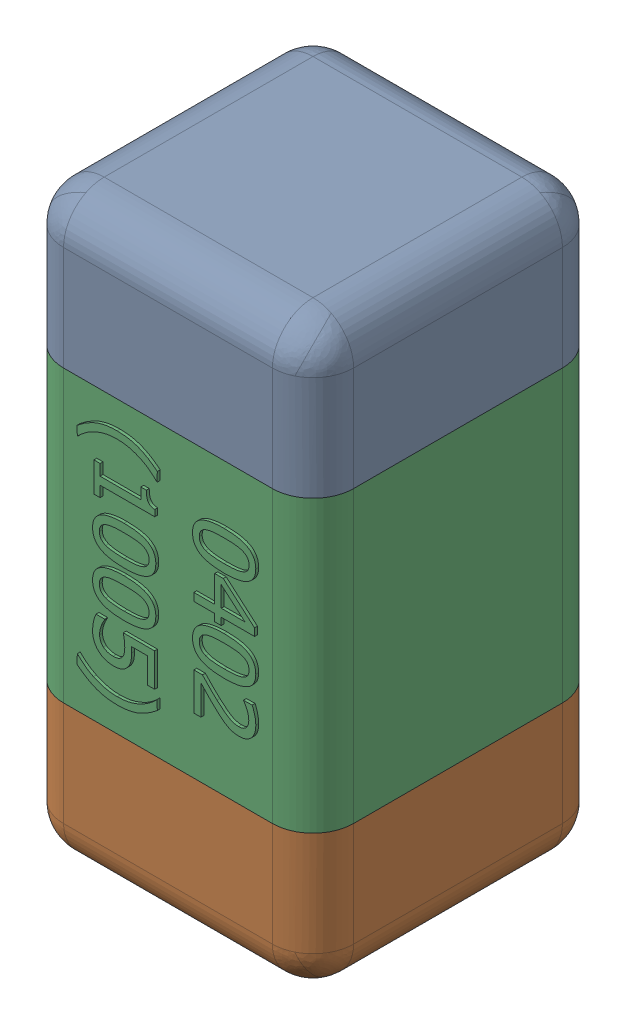
SolidWorks assembly C26, configuration Standard. Lengths in mm.
Overall size (0.51 1.01 0.51).
4 component instances, 3 part files, 0 mates.
Components (placement in the parent):
- C26-subassembly-1-1: C26-subassembly-1 [Standard] at (-9.1 -10.7001 0) x (0 -1 0) z (0 0 1) size (1.01 0.51 0.51)
  - User Library-0402_Cap-1: User Library-0402_Cap [Standard] at origin size (0.26 0.51 0.51)
  - User Library-0402_Cap-1-1: User Library-0402_Cap-1 [Standard] at origin size (0.26 0.5 0.51)
  - User Library-0402_Cap-2-1: User Library-0402_Cap-2 [Standard] at origin size (0.5 0.5 0.51)
